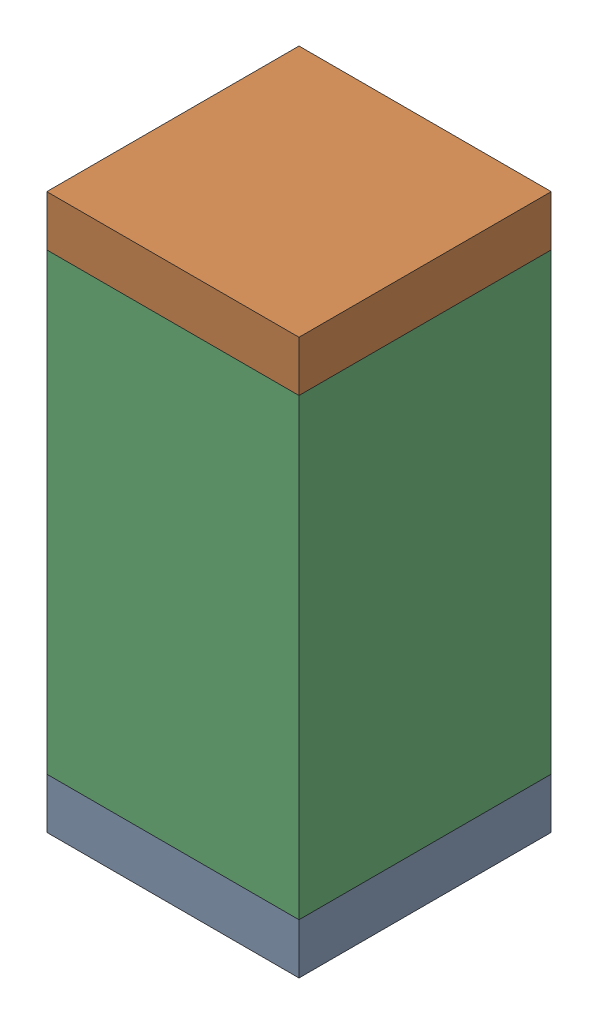
SolidWorks assembly C109, configuration Default. Lengths in mm.
Overall size (0.5 1.1 0.5).
6 component instances, 2 part files, 0 mates.
Components (placement in the parent):
- 810157360-1: 810157360 [Default] at (114.75 79 0) size (0.5 0.1 0.5)
  - Extruded_9-1: Extruded_9 [Default] at origin size (0.5 0.1 0.5)
- 810157360-2: 810157360 [Default] at (114.75 80 0) size (0.5 0.1 0.5)
  - Extruded_9-1: Extruded_9 [Default] at origin size (0.5 0.1 0.5)
- 791586336-1: 791586336 [Default] at (114.75 79.5 0) size (0.5 0.9 0.5)
  - Extruded_8-1: Extruded_8 [Default] at origin size (0.5 0.9 0.5)
